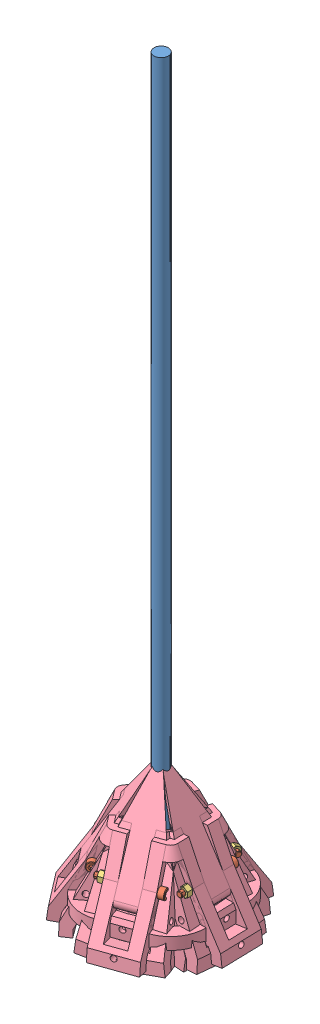
SolidWorks assembly Manipulator - pentagon, configuration Default. Lengths in mm.
Overall size (168.05 643.58 168.59).
18 component instances, 5 part files, 84 mates.
Components (placement in the parent):
- Rope-1: Rope [Default] at origin size (12.7 609.6 12.7)
- socket head cap screw_am-1: socket head cap screw_am [B18.3.1M - 5 x 0.8 x 45 Hex SHCS -- 22CHX] at (-46.7972 -306.4198 -3.6841) x (0.566376 0 -0.824147) z (0.361766 -0.898508 0.248615) size (50 8.5 8.5)
- hex nut style 1_am-1: hex nut style 1_am [B18.2.4.1M - Hex nut, Style 1,  M5 x 0.8 --D-C] at (-23.0444 -306.4198 -38.2474) x (0.824147 0 0.566376) z (-0.566376 0 0.824147) size (8 9.24 4.7)
- hex nut style 1_am-2: hex nut style 1_am [B18.2.4.1M - Hex nut, Style 1,  M5 x 0.8 --D-C] at (41.2484 -306.4198 22.0951) x (0.999313 -0.026214 -0.026205) z (0.026214 0 0.999656) size (8 9.24 4.7)
- hex nut style 1_am-3: hex nut style 1_am [B18.2.4.1M - Hex nut, Style 1,  M5 x 0.8 --D-C] at (-8.2672 -306.4198 46.0566) x (0.333841 0 0.942629) z (-0.942629 0 0.333841) size (8 9.24 4.7)
- hex nut style 1_am-4: hex nut style 1_am [B18.2.4.1M - Hex nut, Style 1,  M5 x 0.8 --D-C] at (33.7609 -306.4198 -32.4016) x (0.28398 0 -0.95883) z (0.95883 0 0.28398) size (8 9.24 4.7)
- hex nut style 1_am-7: hex nut style 1_am [B18.2.4.1M - Hex nut, Style 1,  M5 x 0.8 --D-C] at (-43.3489 -306.4198 10.2891) x (0.793331 0 -0.60879) z (0.60879 0 0.793331) size (8 9.24 4.7)
- Case - Pentagon-1: Case - Pentagon [Default] at (0 -365.6222 0) x (0.793331 0 -0.60879) z (0.60879 0 0.793331) size (159.16 55 159.16) (hidden)
- CASE inside - Pentagon-1: CASE inside - Pentagon [smaller1] at (0.0005 -207.4048 -0.0004) x (0.793331 0 -0.60879) z (-0.60879 0 -0.793331) size (118.58 63.2 121.51)
- CASE inside - Pentagon-2: CASE inside - Pentagon [inside1] at (1.2958 -228.8815 0.8898) x (0.818318 -0.118725 0.56237) z (0.566376 0 -0.824147) size (112.69 120.36 118.49)
- socket head cap screw_am-2: socket head cap screw_am [B18.3.1M - 5 x 0.8 x 45 Hex SHCS -- 22CHX] at (-10.9573 -306.4198 -45.646) x (0.95883 0 0.28398) z (-0.124655 -0.898508 0.420886) size (50 8.5 8.5)
- socket head cap screw_am-3: socket head cap screw_am [B18.3.1M - 5 x 0.8 x 45 Hex SHCS -- 22CHX] at (40.0259 -306.4198 -24.5272) x (0.026214 0 0.999656) z (-0.438807 -0.898508 0.011507) size (50 8.5 8.5)
- socket head cap screw_am-6: socket head cap screw_am [B18.3.1M - 5 x 0.8 x 45 Hex SHCS -- 22CHX] at (35.6954 -306.4198 30.4869) x (-0.942629 0 0.333841) z (0.057237 -0.985193 0.161614) size (50 8.5 8.5)
- socket head cap screw_am-8: socket head cap screw_am [B18.3.1M - 5 x 0.8 x 45 Hex SHCS -- 22CHX] at (-17.9643 -306.4198 43.3686) x (-0.60879 0 -0.793331) z (0.700975 -0.468272 -0.537918) size (50 8.5 8.5)
- CASE inside - Pentagon-3: CASE inside - Pentagon [inside1] at (-0.4461 -228.882 1.5074) x (-0.281971 -0.118736 0.952047) z (0.95883 0 0.28398) size (112.69 120.36 118.49)
- CASE inside - Pentagon-4: CASE inside - Pentagon [inside1] at (-1.5714 -228.882 0.0408) x (-0.992585 -0.118736 0.026028) z (0.026214 0 0.999656) size (112.69 120.36 118.49)
- CASE inside - Pentagon-5: CASE inside - Pentagon [inside1] at (-0.5242 -228.8815 -1.4819) x (-0.33148 -0.118725 -0.935962) z (-0.942629 0 0.333841) size (112.69 120.36 118.49)
- CASE inside - Pentagon-6: CASE inside - Pentagon [inside1] at (1.2469 -228.8812 -0.9569) x (0.787721 -0.118719 -0.604485) z (-0.60879 0 -0.793331) size (112.69 120.36 118.49)
Mates (geometry in assembly coordinates):
- Coincident30: coordinate: point of Rope-1
- Concentric3: concentric aligned: cylinder of Rope-1 through (0 304.8 0) axis (0 -1 0) radius 6.35; cylinder of Case-1 through (0 65.4617 0) axis (0 -1 0) radius 39.6875
- Concentric6: concentric aligned: cylinder of hex clip piece-13 through (0 32.5714 0) axis (0 -1 0) radius 6.35; cylinder of Rope-1 through (0 304.8 0) axis (0 -1 0) radius 6.35
- Concentric7: concentric aligned: cylinder of hex clip piece-7 through (0 33.7354 0) axis (0 -1 0) radius 6.35; cylinder of Rope-1 through (0 304.8 0) axis (0 -1 0) radius 6.35
- Coincident31: coincident anti-aligned: plane of case1 - Copy-1 through (0 308.2534 0) normal (-0.999808 0 -0.019586); plane of case1 - Copy-2 through (0 308.2534 0) normal (0.999808 0 0.019586)
- Concentric8: concentric aligned: cylinder of case1 - Copy-1 through (0 308.2534 0) axis (0 -1 0) radius 6.35; cylinder of case1 - Copy-2 through (0 308.2534 0) axis (0 -1 0) radius 6.35
- Coincident33: coincident aligned: line of case1 - Copy-1 through (-1.0401 114.3867 53.0958) axis (0.014805 -0.654654 -0.755784); line of case1 - Copy-2 through (-1.0401 114.3867 53.0958) axis (0.014805 -0.654654 -0.755784)
- Coincident36: coincident aligned: line of case1 - Copy-2 through (-46.5024 114.3867 25.6471) axis (0.661931 -0.654654 -0.36507); line of case1 - Copy-3 through (-46.5024 114.3867 25.6471) axis (0.661931 -0.654654 -0.36507)
- Coincident37: coincident anti-aligned: plane of case1 - Copy-2 through (0 308.2534 0) normal (-0.482943 0 -0.875652); plane of case1 - Copy-3 through (0 308.2534 0) normal (0.482943 0 0.875652)
- Concentric10: concentric aligned: cylinder of case1 - Copy-2 through (0 308.2534 0) axis (0 -1 0) radius 6.35; cylinder of case1 - Copy-3 through (0 308.2534 0) axis (0 -1 0) radius 6.35
- Concentric11: concentric aligned: cylinder of Rope-1 through (0 304.8 0) axis (0 -1 0) radius 6.35; cylinder of case1 - Copy-2 through (0 308.2534 0) axis (0 -1 0) radius 6.35
- Coincident38: coincident anti-aligned: plane of case1 - Copy-1 through (0 308.2534 0) normal (0.516866 0 -0.856067); plane of case1 - Copy-4 through (0 308.2534 0) normal (-0.516866 0 0.856067)
- Coincident39: coincident aligned: line of case1 - Copy-1 through (45.4623 114.3867 27.4487) axis (-0.647125 -0.654654 -0.390714); line of case1 - Copy-4 through (45.4623 114.3867 27.4487) axis (-0.647125 -0.654654 -0.390714)
- Concentric12: concentric aligned: cylinder of case1 - Copy-1 through (0 308.2534 0) axis (0 -1 0) radius 6.35; cylinder of case1 - Copy-4 through (0 308.2534 0) axis (0 -1 0) radius 6.35
- Coincident40: coincident aligned: line of case1 - Copy-4 through (46.5024 114.3867 -25.6471) axis (-0.661931 -0.654654 0.36507); line of case1 - Copy-5 through (46.5024 114.3867 -25.6471) axis (-0.661931 -0.654654 0.36507)
- Coincident41: coincident anti-aligned: plane of case1 - Copy-4 through (0 308.2534 0) normal (-0.482943 0 -0.875652); plane of case1 - Copy-5 through (0 308.2534 0) normal (0.482943 0 0.875652)
- Concentric13: concentric aligned: cylinder of case1 - Copy-4 through (0 308.2534 0) axis (0 -1 0) radius 6.35; cylinder of case1 - Copy-5 through (0 308.2534 0) axis (0 -1 0) radius 6.35
- Coincident42: coincident aligned: line of case1 - Copy-5 through (1.0401 114.3867 -53.0958) axis (-0.014805 -0.654654 0.755784); line of case1 - Copy-6 through (1.0401 114.3867 -53.0958) axis (-0.014805 -0.654654 0.755784)
- Coincident43: coincident anti-aligned: plane of case1 - Copy-5 through (0 308.2534 0) normal (-0.999808 0 -0.019586); plane of case1 - Copy-6 through (0 308.2534 0) normal (0.999808 0 0.019586)
- Concentric15: concentric aligned: cylinder of case1 - Copy-5 through (0 308.2534 0) axis (0 -1 0) radius 6.35; cylinder of case1 - Copy-6 through (0 308.2534 0) axis (0 -1 0) radius 6.35
- Coincident47: coincident anti-aligned: plane of Case-1 through (-49.48 183.4736 45.118) normal (0.738927 0 -0.673785); plane of case1 - Copy - Copy-1 through (-83.412 -86.1077 -16.2015) normal (-0.878007 0 -0.478649)
- Concentric16: concentric aligned: cylinder of Case-1 through (-83.2151 85.4617 -26.4615) axis (0.952979 0 0.303037) radius 2.5; cylinder of CASE inside-1 through (-2.1142 35 -86.3346) axis (0.024481 0 0.9997) radius 2.5
- Coincident49: coincident: plane of CASE inside-1 through (0 118.6333 0) normal (-0.021201 0.5 -0.865766); plane of copy-1 through (-0.054 116.4277 -2.2049) normal (-0.017311 0.707107 -0.706895)
- Parallel2: parallel: plane of CASE inside-1 through (-36.6205 -135.3667 -65.7449) normal (0.024481 0 0.9997); plane of copy-1 through (-39.7581 -137.5723 -67.2435) normal (-0.024481 0 -0.9997)
- Coincident51: coincident anti-aligned: plane of CASE inside-1; plane of copy-1 through (-19.7641 36.2944 -67.7331) normal (-0.9997 0 0.024481)
- Width1: width anti-aligned: plane of CASE inside-2 through (-22.31 93.354 -48.3056) normal (0.976822 0 -0.214052); plane of CASE inside-2 through (0.0651 93.354 -53.2087) normal (-0.976822 0 0.214052); plane of CASE inside-3 through (-22.8744 86.025 -50.8814) normal (-0.976822 0 0.214052); plane of CASE inside-3 through (-0.4993 86.025 -55.7844) normal (0.976822 0 -0.214052)
- Concentric18: concentric anti-aligned: cylinder of CASE inside-2 through (17.4897 109.4162 -53.4439) axis (-0.976822 0 0.214052) radius 2.5; cylinder of CASE inside-3 through (-39.1931 109.4162 -41.023) axis (0.976822 0 -0.214052) radius 2.5
- Concentric23: concentric aligned: cylinder of Case-1 through (83.2151 85.4617 26.4615) axis (-0.952979 0 -0.303037) radius 2.5; cylinder of CASE inside-2 through (63.8129 85.4617 20.2918) axis (-0.952979 0 -0.303037) radius 2.5
- Coincident54: coincident anti-aligned: plane of Case-1 through (63.8133 183.4736 20.2919) normal (-0.952979 0 -0.303037); plane of CASE inside-2 through (72.904 -50.646 -8.2976) normal (0.952979 0 0.303037)
- Concentric27: concentric aligned: cylinder of Case-1 through (-64.5239 85.4617 58.8356) axis (0.738927 0 -0.673785) radius 2.5; cylinder of CASE inside-2 through (-49.4797 85.4617 45.1177) axis (0.738927 0 -0.673785) radius 2.5
- Coincident55: coincident anti-aligned: plane of CASE inside-2 through (-52.9889 93.354 -4.8318) normal (0.303037 0 -0.952979); plane of CASE inside-4 through (-53.3874 85.553 -4.9585) normal (-0.303037 0 0.952979)
- Concentric28: concentric anti-aligned: cylinder of CASE inside-2 through (-37.539 109.4162 -41.8685) axis (-0.303037 0 0.952979) radius 2.5; cylinder of CASE inside-4 through (-55.1235 109.4162 13.4307) axis (0.303037 0 -0.952979) radius 2.5
- Coincident59: coincident anti-aligned: plane of CASE inside-2 through (-30.6789 93.354 43.4738) normal (-0.673785 0 -0.738927); plane of CASE inside-6 through (-31.5132 85.6806 44.2346) normal (0.673785 0 0.738927)
- Concentric30: concentric anti-aligned: cylinder of CASE inside-2 through (-55.0286 109.4162 11.5755) axis (0.673785 0 0.738927) radius 2.5; cylinder of CASE inside-6 through (-15.9304 109.4162 54.4537) axis (-0.673785 0 -0.738927) radius 2.5
- Coincident60: coincident anti-aligned: plane of CASE inside-2 through (22.31 93.354 48.3056) normal (-0.976822 0 0.214052); plane of CASE inside-7 through (22.8488 85.9939 50.7643) normal (0.976822 0 -0.214052)
- Concentric31: concentric anti-aligned: cylinder of CASE inside-2 through (-17.4897 109.4162 53.4439) axis (0.976822 0 -0.214052) radius 2.5; cylinder of CASE inside-7 through (39.1931 109.4162 41.023) axis (-0.976822 0 0.214052) radius 2.5
- Coincident61: coincident anti-aligned: plane of CASE inside-2 through (52.9889 93.354 4.8318) normal (-0.303037 0 0.952979); plane of CASE inside-9 through (55.5835 86.0477 5.6569) normal (0.303037 0 -0.952979)
- Concentric32: concentric anti-aligned: cylinder of CASE inside-2 through (37.539 109.4162 41.8685) axis (0.303037 0 -0.952979) radius 2.5; cylinder of CASE inside-9 through (55.1235 109.4162 -13.4307) axis (-0.303037 0 0.952979) radius 2.5
- Coincident62: coincident anti-aligned: plane of CASE inside-2 through (30.6789 93.354 -43.4738) normal (0.673785 0 0.738927); plane of CASE inside-10 through (32.5446 85.9959 -45.175) normal (-0.673785 0 -0.738927)
- Concentric34: concentric anti-aligned: cylinder of CASE inside-2 through (55.0286 109.4162 -11.5755) axis (-0.673785 0 -0.738927) radius 2.5; cylinder of CASE inside-10 through (15.9304 109.4162 -54.4537) axis (0.673785 0 0.738927) radius 2.5
- Coincident63: coincident anti-aligned: plane of CASE inside-2 through (32.0782 93.354 46.1651) normal (0.976822 0 -0.214052); plane of socket button head cap screw_am-5 through (30.9637 111.2432 41.0793) normal (-0.976822 0 0.214052)
- Concentric35: concentric aligned: cylinder of CASE inside-2 through (-17.4897 109.4162 53.4439) axis (0.976822 0 -0.214052) radius 2.5; cylinder of socket button head cap screw_am-5 through (34.0153 109.4162 42.1576) axis (0.976822 0 -0.214052) radius 2.5
- Coincident64: coincident anti-aligned: plane of CASE inside-2 through (-32.0782 93.354 -46.1651) normal (-0.976822 0 0.214052); plane of socket head cap screw_am-1 through (-40.8189 -304.5543 -5.6423) normal (0.566376 0 -0.824147)
- Concentric36: concentric aligned: cylinder of CASE inside-2 through (17.4897 109.4162 -53.4439) axis (-0.976822 0 0.214052) radius 2.5; cylinder of socket head cap screw_am-1 through (-64.7804 -306.4198 22.4823) axis (-0.566376 0 0.824147) radius 2.5
- Coincident65: coincident anti-aligned: plane of CASE inside-2 through (9.8333 93.354 -55.3492) normal (0.976822 0 -0.214052); plane of hex nut style 1_am-1 through (-29.6382 -306.4198 -42.7787) normal (-0.566376 0 0.824147)
- Concentric37: concentric aligned: cylinder of socket head cap screw_am-1 through (-64.7804 -306.4198 22.4823) axis (-0.566376 0 0.824147) radius 2.5; cylinder of hex nut style 1_am-1 through (-20.3831 -306.4198 -42.1211) axis (-0.566376 0 0.824147) radius 2.1
- Concentric38: concentric aligned: cylinder of Rope-1 through (0 304.8 0) axis (0 -1 0) radius 6.35; cylinder of Case - Pentagon-1 through (0 -350.6222 0) axis (0 -1 0) radius 39.6875
- Coincident66: coincident anti-aligned: plane of Case - Pentagon-1 through (-44.6576 -227.7106 34.2696) normal (0.793331 0 -0.60879); plane of CASE inside - Pentagon-1 through (-26.3943 -461.4048 58.0691) normal (-0.793331 0 0.60879)
- Concentric39: concentric anti-aligned: cylinder of Case - Pentagon-1 through (-79.5524 -330.6222 61.0473) axis (0.793331 0 -0.60879) radius 2.5; cylinder of CASE inside - Pentagon-1 through (58.5261 -330.6222 -44.9128) axis (-0.793331 0 0.60879) radius 2.5
- Coincident67: coincident anti-aligned: plane of Case - Pentagon-1 through (18.7924 -227.7106 53.0618) normal (-0.333841 0 -0.942629); plane of CASE inside - Pentagon-1 through (47.0711 -461.4048 43.0462) normal (0.333841 0 0.942629)
- Concentric40: concentric anti-aligned: cylinder of Case - Pentagon-1 through (33.4764 -330.6222 94.5235) axis (-0.333841 0 -0.942629) radius 2.5; cylinder of CASE inside - Pentagon-1 through (-24.6286 -330.6222 -69.541) axis (0.333841 0 0.942629) radius 2.5
- Coincident68: coincident anti-aligned: plane of CASE inside - Pentagon-1 through (-29.2337 -319.6166 -30.3669) normal (-0.566376 0 0.824147); plane of CASE inside - Pentagon-2 through (-38.1947 -335.6349 -36.5251) normal (0.566376 0 -0.824147)
- Concentric41: concentric anti-aligned: cylinder of CASE inside - Pentagon-1 through (-19.0402 -306.4198 -44.0753) axis (-0.566376 0 0.824147) radius 2.5; cylinder of CASE inside - Pentagon-2 through (-67.0603 -306.4198 25.7999) axis (0.566376 0 -0.824147) radius 2.5
- Concentric42: concentric aligned: cylinder of socket head cap screw_am-1 through (-64.7804 -306.4198 22.4823) axis (-0.566376 0 0.824147) radius 2.5; cylinder of CASE inside - Pentagon-1 through (-19.0402 -306.4198 -44.0753) axis (-0.566376 0 0.824147) radius 2.5
- Coincident69: coincident anti-aligned: plane of hex nut style 1_am-1 through (-29.6382 -306.4198 -42.7787) normal (-0.566376 0 0.824147); plane of CASE inside - Pentagon-1 through (-23.5699 -319.6166 -38.6084) normal (0.566376 0 -0.824147)
- Coincident70: coincident anti-aligned: plane of socket head cap screw_am-1 through (-40.8189 -304.5543 -5.6423) normal (0.566376 0 -0.824147); plane of CASE inside - Pentagon-1 through (-44.4909 -319.6166 -8.1658) normal (-0.566376 0 0.824147)
- Coincident71: coincident anti-aligned: plane of CASE inside - Pentagon-1 through (-5.983 -319.6166 -44.8369) normal (-0.95883 0 -0.28398); plane of socket head cap screw_am-2 through (-7.2483 -304.5543 -40.5648) normal (0.95883 0 0.28398)
- Concentric43: concentric aligned: cylinder of CASE inside - Pentagon-1 through (36.0336 -306.4198 -31.7285) axis (-0.95883 0 -0.28398) radius 2.5; cylinder of socket head cap screw_am-2 through (-41.4009 -306.4198 -54.6626) axis (-0.95883 0 -0.28398) radius 2.5
- Concentric44: concentric anti-aligned: cylinder of hex nut style 1_am-4 through (29.2537 -306.4198 -33.7365) axis (0.95883 0 0.28398) radius 2.1; cylinder of socket head cap screw_am-2 through (-41.4009 -306.4198 -54.6626) axis (-0.95883 0 -0.28398) radius 2.5
- Coincident72: coincident anti-aligned: plane of hex nut style 1_am-4 through (26.9818 -306.4198 -26.0659) normal (-0.95883 0 -0.28398); plane of CASE inside - Pentagon-1 through (29.4345 -319.6166 -34.3472) normal (0.95883 0 0.28398)
- Coincident731: coincident anti-aligned: plane of CASE inside - Pentagon-1 through (40.7929 -319.6166 -19.5458) normal (-0.026214 0 -0.999656); plane of socket head cap screw_am-3 through (36.3389 -304.5543 -19.429) normal (0.026214 0 0.999656)
- Coincident741: coincident anti-aligned: plane of CASE inside - Pentagon-1 through (31.1942 -319.6166 32.7562) normal (0.942629 0 -0.333841); plane of socket head cap screw_am-6 through (29.5837 -307.1485 28.209) normal (-0.942629 0 0.333841)
- Coincident751: coincident anti-aligned: plane of CASE inside - Pentagon-1 through (-21.5142 -319.6166 39.7894) normal (0.60879 0 0.793331); plane of socket head cap screw_am-8 through (-19.4301 -302.6646 38.1901) normal (-0.60879 0 -0.793331)
- Concentric451: concentric aligned: cylinder of CASE inside - Pentagon-1 through (41.3099 -306.4198 24.4652) axis (-0.026214 0 -0.999656) radius 2.5; cylinder of socket head cap screw_am-3 through (39.1929 -306.4198 -56.2665) axis (-0.026214 0 -0.999656) radius 2.5
- Concentric461: concentric aligned: cylinder of CASE inside - Pentagon-1 through (-10.503 -306.4198 46.848) axis (0.942629 0 -0.333841) radius 2.5; cylinder of socket head cap screw_am-6 through (65.6232 -306.4198 19.8872) axis (0.942629 0 -0.333841) radius 2.5
- Concentric471: concentric aligned: cylinder of CASE inside - Pentagon-1 through (-47.8014 -306.4198 4.4877) axis (0.60879 0 0.793331) radius 2.5; cylinder of socket head cap screw_am-8 through (1.3641 -306.4198 68.5566) axis (0.60879 0 0.793331) radius 2.5
- Concentric481: concentric anti-aligned: cylinder of hex nut style 1_am-2 through (41.1245 -306.4198 17.3965) axis (0.026214 0 0.999656) radius 2.1; cylinder of socket head cap screw_am-3 through (39.1929 -306.4198 -56.2665) axis (-0.026214 0 -0.999656) radius 2.5
- Coincident761: coincident anti-aligned: circle of hex nut style 1_am-3; cylinder of socket head cap screw_am-6 through (65.6239 -306.4198 19.8874) axis (0.942629 0 -0.333841) radius 2.5
- Concentric491: concentric aligned: cylinder of hex nut style 1_am-7 through (-46.2106 -306.4198 6.5607) axis (0.60879 0 0.793331) radius 2.1; cylinder of socket head cap screw_am-8 through (1.3641 -306.4198 68.5566) axis (0.60879 0 0.793331) radius 2.5
- Coincident771: coincident anti-aligned: plane of hex nut style 1_am-2 through (33.13 -306.2101 17.6062) normal (-0.026214 0 -0.999656); plane of CASE inside - Pentagon-1 through (41.7612 -319.6166 17.3798) normal (0.026214 0 0.999656)
- Coincident781: coincident anti-aligned: plane of hex nut style 1_am-3 through (-6.5083 -306.4198 36.9464) normal (0.942629 0 -0.333841); plane of CASE inside - Pentagon-1 through (-3.625 -319.6166 45.0877) normal (-0.942629 0 0.333841)
- Concentric501: concentric anti-aligned: cylinder of socket head cap screw_am-2 through (-41.4009 -306.4198 -54.6626) axis (-0.95883 0 -0.28398) radius 2.5; cylinder of CASE inside - Pentagon-3 through (-45.2607 -306.4198 -55.8057) axis (0.95883 0 0.28398) radius 2.5
- Coincident801: coincident anti-aligned: plane of CASE inside - Pentagon-1 through (3.6053 -319.6166 -41.9971) normal (0.95883 0 0.28398); plane of CASE inside - Pentagon-3 through (6.8594 -335.3972 -52.9844) normal (-0.95883 0 -0.28398)
- Concentric511: concentric anti-aligned: cylinder of socket head cap screw_am-3 through (39.1929 -306.4198 -56.2665) axis (-0.026214 0 -0.999656) radius 2.5; cylinder of CASE inside - Pentagon-4 through (39.0874 -306.4198 -60.2906) axis (0.026214 0 0.999656) radius 2.5
- Coincident811: coincident anti-aligned: plane of CASE inside - Pentagon-1 through (41.0551 -319.6166 -9.5492) normal (0.026214 0 0.999656); plane of CASE inside - Pentagon-4 through (52.5098 -335.3974 -9.8496) normal (-0.026214 0 -0.999656)
- Concentric521: concentric anti-aligned: cylinder of socket head cap screw_am-6 through (65.6232 -306.4198 19.8872) axis (0.942629 0 -0.333841) radius 2.5; cylinder of CASE inside - Pentagon-5 through (69.4177 -306.4198 18.5433) axis (-0.942629 0 0.333841) radius 2.5
- Coincident821: coincident anti-aligned: plane of CASE inside - Pentagon-1 through (21.7679 -319.6166 36.0946) normal (-0.942629 0 0.333841); plane of CASE inside - Pentagon-5 through (25.3973 -335.6354 46.3427) normal (0.942629 0 -0.333841)
- Concentric531: concentric anti-aligned: cylinder of socket head cap screw_am-8 through (1.3641 -306.4198 68.5566) axis (0.60879 0 0.793331) radius 2.5; cylinder of CASE inside - Pentagon-6 through (3.8148 -306.4198 71.7502) axis (-0.60879 0 -0.793331) radius 2.5
- Coincident831: coincident anti-aligned: plane of CASE inside - Pentagon-1 through (-27.6021 -319.6166 31.8561) normal (-0.60879 0 -0.793331); plane of CASE inside - Pentagon-6 through (-36.6926 -335.3974 38.832) normal (0.60879 0 0.793331)
- Tangent1: tangent: curve of Rope-1 through (0 304.8 0) axis (0 -1 0) radius 6.35; edge_curve of CASE inside - Pentagon-5
- Tangent2: tangent: cylinder of Rope-1 through (0 304.8 0) axis (0 -1 0) radius 6.35; edge_curve of CASE inside - Pentagon-6
- Tangent3: tangent: cylinder of Rope-1 through (0 304.8 0) axis (0 -1 0) radius 6.35; edge_curve of CASE inside - Pentagon-2
- Tangent4: tangent: cylinder of Rope-1 through (0 304.8 0) axis (0 -1 0) radius 6.35; edge_curve of CASE inside - Pentagon-3
- Tangent5: tangent: cylinder of Rope-1 through (0 304.8 0) axis (0 -1 0) radius 6.35; edge_curve of CASE inside - Pentagon-4
